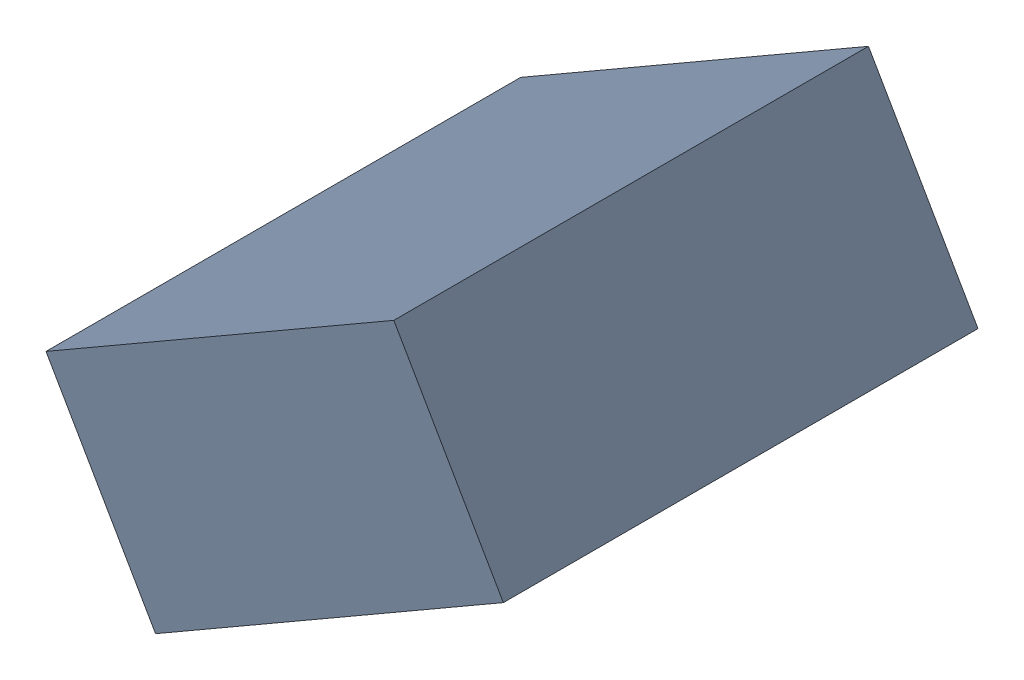
SolidWorks assembly C25_TDA2, configuration Standard. Lengths in mm.
Overall size (1.25 1.07 1.3).
2 component instances, 1 part files, 0 mates.
Components (placement in the parent):
- 885542920-1: 885542920 [Standard] at (36.091 21.4836 0) size (1.25 1.07 1.3)
  - Extruded_24-1: Extruded_24 [Standard] at origin size (1.25 1.07 1.3)
